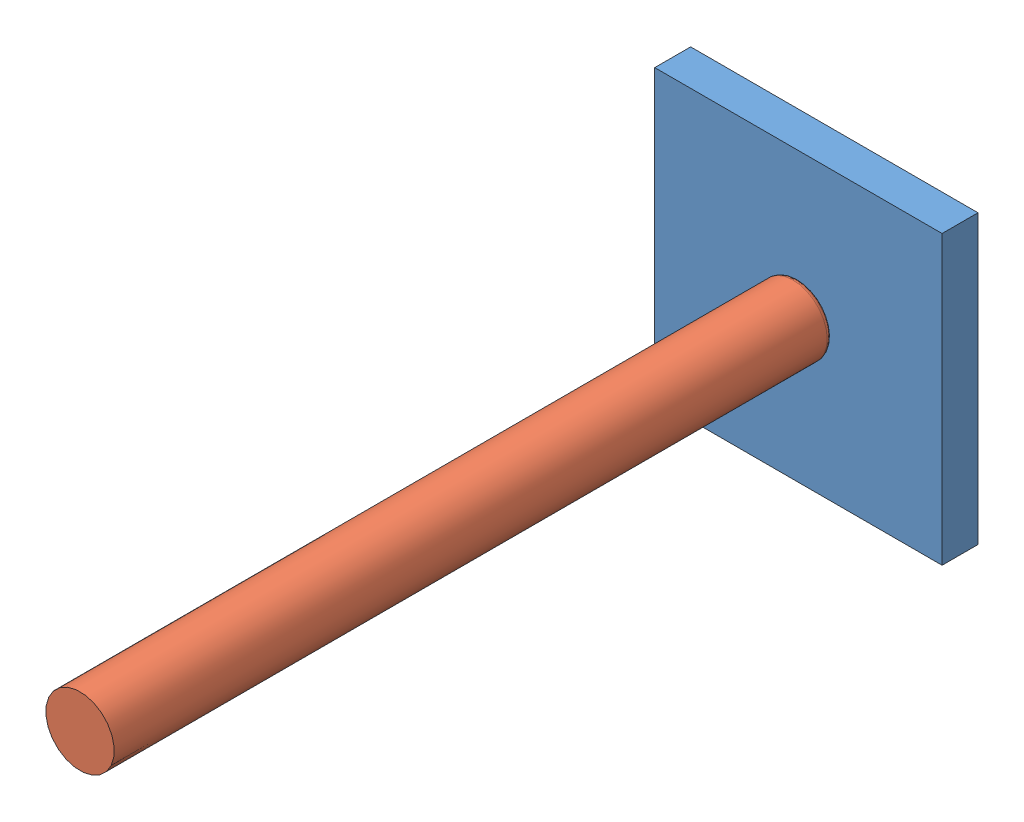
SolidWorks assembly Camera Base, configuration Default. Lengths in mm.
Overall size (80 80 210).
2 component instances, 2 part files, 2 mates.
Components (placement in the parent):
- Base-1: Base [Default] at origin size (80 80 10)
- Rod-1: Rod [Default] at (0 0 210) x (-0.407827 -0.913059 0) z (0.913059 -0.407827 0) size (19.05 200 19.05)
Mates (geometry in assembly coordinates):
- Coincident1: coincident: plane of Base-1 through (0 0 10) normal (0 0 1); plane of Rod-1 through (0 0 10) normal (0 0 -1)
- Concentric1: concentric aligned: circle of Rod-1
